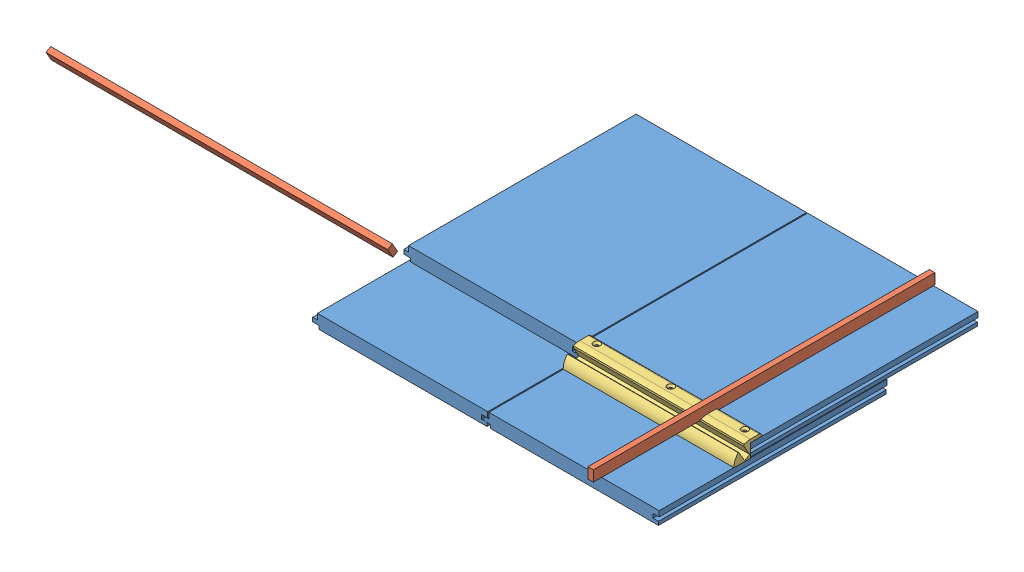
SolidWorks assembly Headboard Ceiling, configuration Default. Lengths in mm.
Overall size (773.34 42.77 381).
8 component instances, 4 part files, 22 mates.
Components (placement in the parent):
- Floor Board-2: Floor Board [Default] at origin size (195.2 14.66 254)
- Floor Board-3: Floor Board [Default] at (191.262 0 0) size (195.2 14.66 254)
- Floor Board-4: Floor Board [Default] at (0 14.6558 -101.6) size (195.2 14.66 254)
- Floor Board-5: Floor Board [Default] at (191.262 14.6558 -101.6) size (195.2 14.66 254)
- Aclorol LED Neon Rope Lights Addressable LED Strip-1: Aclorol LED Neon Rope Lights Addressable LED Strip [Default] at (-296.3315 15.2785 32.2721) x (1 0 0) z (0 0.5 -0.866025) size (381 11.94 6.05)
- Part1^Headboard Ceiling-1: Part1^Headboard Ceiling [Default] at origin (virtual)
- Headboard Ceiling LED Mount V1-1: Headboard Ceiling LED Mount V1 [Default] at (191.262 0 0) x (0 0 -1) z (1 0 0) size (31.17 18.47 190.5)
- Aclorol LED Neon Rope Lights Addressable LED Strip-2: Aclorol LED Neon Rope Lights Addressable LED Strip [Default] at (235.1451 29.4767 -38.1) x (0 0 -1) z (-1 0 0) size (381 11.94 6.05)
Mates (geometry in assembly coordinates):
- Coincident1: coordinate: point of Floor Board-2
- Distance1: distance = 1.27 mm anti-aligned: plane of Floor Board-2 through (94.996 0 127) normal (1 0 0); plane of Floor Board-3 through (96.266 0 127) normal (-1 0 0)
- Coincident4: coincident aligned: plane of Floor Board-2 through (0 7.3279 127) normal (0 1 0); plane of Floor Board-3 through (191.262 7.3279 127) normal (0 1 0)
- Coincident5: coincident anti-aligned: plane of Floor Board-2 through (0 7.3279 127) normal (0 1 0); plane of Floor Board-4 through (0 7.3279 25.4) normal (0 -1 0)
- Coincident6: coincident aligned: plane of Floor Board-2 through (-94.996 0 127) normal (-1 0 0); plane of Floor Board-4 through (-94.996 14.6558 25.4) normal (-1 0 0)
- Coincident7: coincident aligned: plane of Floor Board-4 through (0 21.9837 25.4) normal (0 1 0); plane of Floor Board-5 through (191.262 21.9837 25.4) normal (0 1 0)
- Coincident10: coincident aligned: plane of Floor Board-3 through (96.266 0 127) normal (-1 0 0); plane of Floor Board-5 through (96.266 14.6558 25.4) normal (-1 0 0)
- Coincident11: coincident aligned: plane of Floor Board-2 through (0 0 127) normal (0 0 1); plane of Floor Board-3 through (191.262 0 127) normal (0 0 1)
- Coincident12: coincident aligned: plane of Floor Board-4 through (0 14.6558 25.4) normal (0 0 1); plane of Floor Board-5 through (191.262 14.6558 25.4) normal (0 0 1)
- Distance2: distance = 101.6 mm aligned: plane of Floor Board-5 through (191.262 14.6558 25.4) normal (0 0 1); plane of Floor Board-3 through (191.262 0 127) normal (0 0 1)
- InPlace1: in place: plane of Floor Board-3 through (191.262 0 0) normal (1 0 0); plane of Headboard Ceiling LED Mount V1-1 through (191.262 0 0) normal (1 0 0); moOrthogonalPlaneRef_w of Floor Board-3 through (191.262 0 0) normal (1 0 0); plane of Headboard Ceiling LED Mount V1-1 through (191.262 0 0) normal (0 1 0); plane of Floor Board-3 through (191.262 0 0) normal (1 0 0); plane of Headboard Ceiling LED Mount V1-1 through (191.262 0 0) normal (0 0 -1); plane of Floor Board-3 through (191.262 0 0) normal (1 0 0); unknown of Headboard Ceiling LED Mount V1-1
- Coincident13: coincident aligned: plane of Floor Board-3; plane of Headboard Ceiling LED Mount V1-1
- Coincident14: coincident aligned: moOrthogonalPlaneRef_w of Floor Board-3 through (-8.0607 191.262 0) axis (0 0 1); plane of Headboard Ceiling LED Mount V1-1 through (191.262 0 0) normal (0 1 0)
- Coincident15: coincident anti-aligned: moOrthogonalPlaneRef_w of Floor Board-3 through (0 0 0) axis (1 0 0); plane of Headboard Ceiling LED Mount V1-1 through (191.262 0 0) normal (0 0 -1)
- Parallel1: parallel aligned: plane of Aclorol LED Neon Rope Lights Addressable LED Strip-1 through (-296.3315 15.2785 32.2721) normal (1 0 0)
- Angle2: planar angle = 0.523599 rad aligned: plane of Aclorol LED Neon Rope Lights Addressable LED Strip-1 through (-105.8315 21.9591 32.639) normal (0 0.866025 0.5); plane of Floor Board-3 through (191.262 7.3279 127) normal (0 1 0)
- Distance3: distance = 1.27 mm: line of Aclorol LED Neon Rope Lights Addressable LED Strip-1 through (-105.8315 11.6205 26.67) axis (-1 0 0); plane of Floor Board-5 through (191.262 14.6558 25.4) normal (0 0 1)
- Distance4: distance = 1.27 mm: line of Aclorol LED Neon Rope Lights Addressable LED Strip-1 through (-105.8315 8.5979 31.9053) axis (-1 0 0); plane of Floor Board-3 through (191.262 7.3279 127) normal (0 1 0)
- Parallel2: parallel anti-aligned: plane of Floor Board-5 through (191.262 21.9837 25.4) normal (0 1 0); plane of Aclorol LED Neon Rope Lights Addressable LED Strip-2 through (232.1225 23.5077 -228.6) normal (0 -1 0)
- Parallel3: parallel anti-aligned: plane of Floor Board-5 through (286.258 14.6558 25.4) normal (1 0 0); plane of Aclorol LED Neon Rope Lights Addressable LED Strip-2 through (232.1225 23.5077 -228.6) normal (-1 0 0)
- Distance5: distance = 1.524 mm anti-aligned: plane of Floor Board-5 through (191.262 21.9837 25.4) normal (0 1 0); plane of Aclorol LED Neon Rope Lights Addressable LED Strip-2 through (232.1225 23.5077 -228.6) normal (0 -1 0)
- Coincident16: coincident aligned: plane of Floor Board-5 through (191.262 14.6558 -228.6) normal (0 0 -1); plane of Aclorol LED Neon Rope Lights Addressable LED Strip-2 through (235.1451 29.4767 -228.6) normal (0 0 -1)
